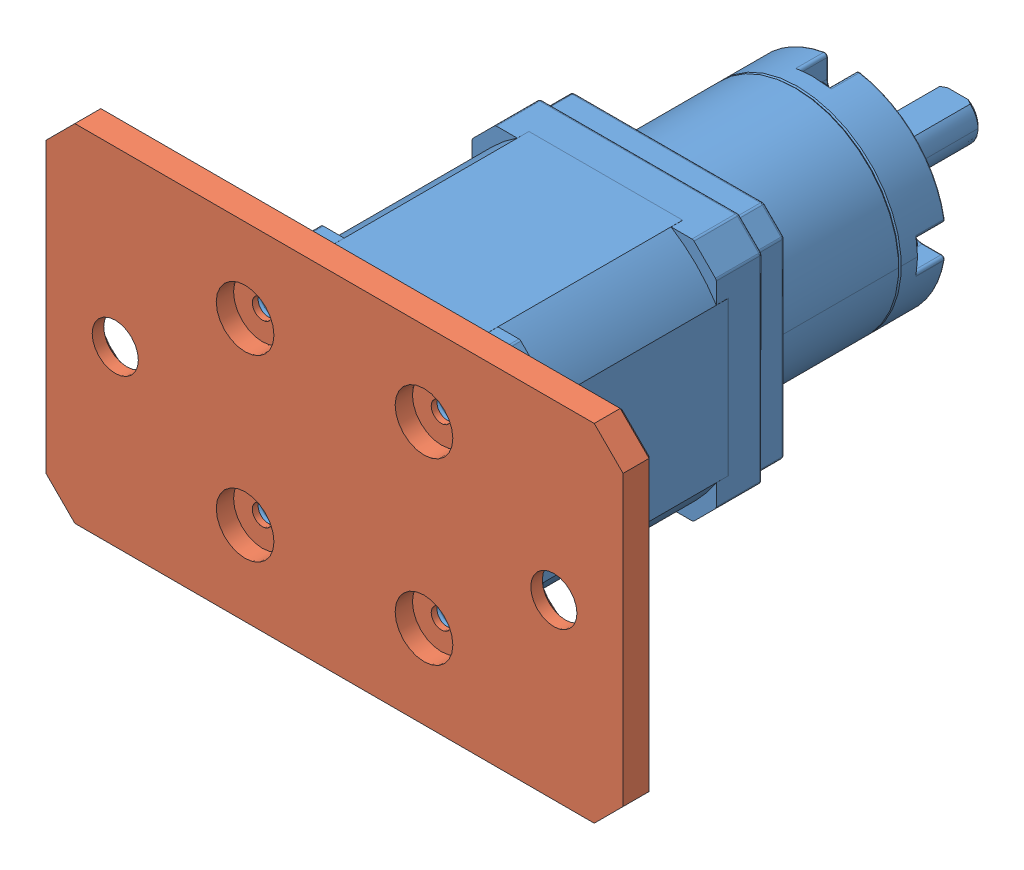
SolidWorks assembly Assem1, configuration Domyślna. Lengths in mm.
Overall size (100 69.15 108.01).
2 component instances, 2 part files, 4 mates.
Components (placement in the parent):
- 17HS19-1684S-PG14.step-1: 17HS19-1684S-PG14.step [Domyślna] at (10.2901 4.3314 106.5114) size (42.32 60.31 103.01)
- Part4-1: Part4 [Domyślna] at (10.2901 4.3314 154.5114) size (100 60 5)
Mates (geometry in assembly coordinates):
- InPlace1: in place: plane of 17HS19-1684S-PG14.step-1 through (10.2901 4.3314 154.5114) normal (0 0 1); plane of ? through (0 0 154.5114) normal (0 0 1); moOrthogonalPlaneRef_w of 17HS19-1684S-PG14.step-1 through (10.2901 4.3314 154.5114) normal (0 0 1); plane of ? through (0 0 154.5114) normal (0 1 0); plane of 17HS19-1684S-PG14.step-1 through (10.2901 4.3314 154.5114) normal (0 0 1); plane of ? through (0 0 154.5114) normal (1 0 0); plane of 17HS19-1684S-PG14.step-1 through (10.2901 4.3314 154.5114) normal (0 0 1); unknown of Part4-1
- Coincident1: coincident aligned: plane of ?; plane of ?
- Coincident2: coincident aligned: moOrthogonalPlaneRef_w of 17HS19-1684S-PG14.step-1 through (10.2901 4.3314 154.5114) normal (0 1 0); plane of Part4^Assem1-1 through (10.2901 4.3314 154.5114) normal (0 1 0)
- Coincident3: coincident anti-aligned: moOrthogonalPlaneRef_w of 17HS19-1684S-PG14.step-1 through (10.2901 4.3314 154.5114) normal (-1 0 0); plane of Part4^Assem1-1 through (10.2901 4.3314 154.5114) normal (1 0 0)
